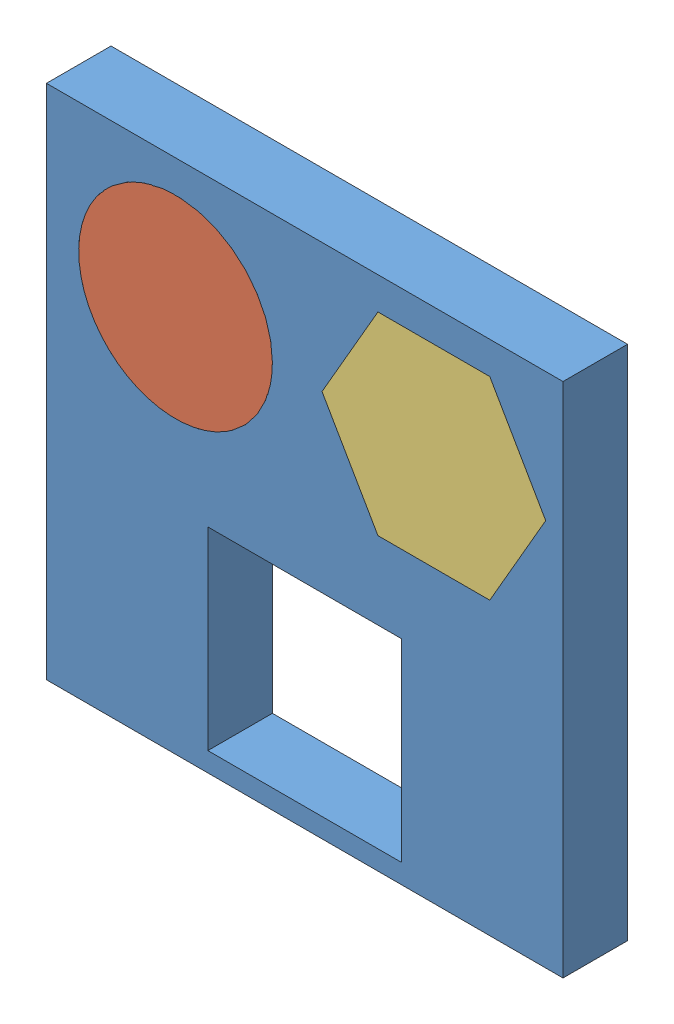
SolidWorks assembly Assem2, configuration Default. Lengths in mm.
Overall size (80 80 10).
3 component instances, 3 part files, 8 mates.
Components (placement in the parent):
- Part1_Assemb-1: Part1_Assemb [Default] at (-20 -20 10) size (80 80 10)
- Part2_Assemb-1: Part2_Assemb [Default] at (-40 0 0) x (0.995156 0.09831 0) z (0 0 1) size (30 30 10)
- Part3_Assemb-1: Part3_Assemb [Default] at origin size (34.64 30 10)
Mates (geometry in assembly coordinates):
- Perpendicular1: perpendicular: plane of assembly through (0 0 0) normal (0 1 0); plane of Part1_Assemb-1 through (-20 -20 10) normal (0 0 1); plane of assembly
- Perpendicular2: perpendicular: plane of assembly through (0 0 0) normal (0 0 1); plane of Part1_Assemb-1 through (-20 -20 10) normal (0 1 0); plane of assembly
- Parallel1: parallel: plane of assembly through (0 0 0) normal (1 0 0); plane of Part1_Assemb-1 through (-20 -20 10) normal (1 0 0); plane of assembly
- Concentric1: concentric: cylinder of assembly; cylinder of assembly; cylinder of Part1_Assemb-1 through (-40 0 0) axis (0 0 1) radius 15; cylinder of Part2_Assemb-1 through (-40 0 10) axis (0 0 -1) radius 15
- Coincident4: coincident: plane of assembly; plane of assembly; plane of Part1_Assemb-1 through (-20 -20 10) normal (0 0 1); plane of Part2_Assemb-1 through (-40 0 10) normal (0 0 1)
- Coincident7: coincident: plane of assembly; plane of assembly; plane of Part1_Assemb-1 through (17.3205 0 0) normal (-0.866025 -0.5 0); plane of Part3_Assemb-1 through (17.3205 0 10) normal (0.866025 0.5 0)
- Coincident8: coincident: plane of assembly; plane of assembly; plane of Part1_Assemb-1 through (-20 -20 10) normal (0 0 1); plane of Part3_Assemb-1 through (0 0 10) normal (0 0 1)
- Coincident12: coincident: line of assembly; line of assembly; line of Part1_Assemb-1 through (-8.6603 15 10) axis (-0.5 -0.866025 0); line of Part3_Assemb-1 through (-8.6603 15 10) axis (-0.5 -0.866025 0)
